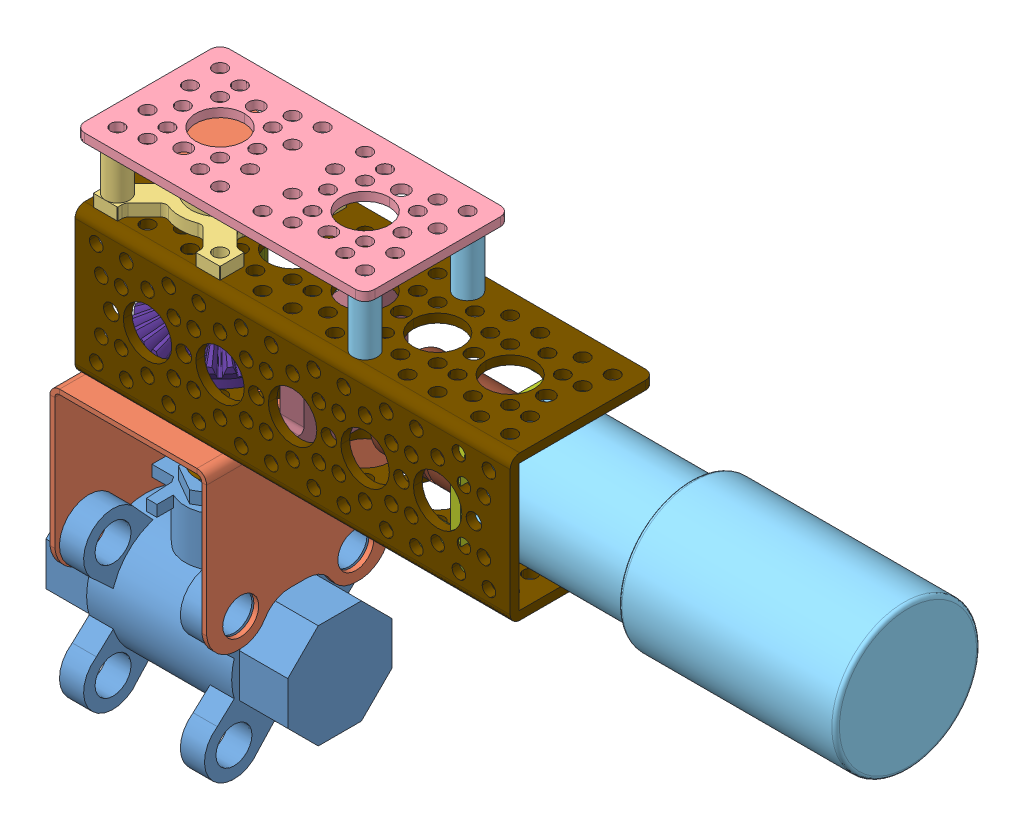
SolidWorks assembly MFV v3.1, configuration Default. Lengths in mm.
Overall size (226.04 151.59 90.41).
38 component instances, 23 part files, 48 mates.
Components (placement in the parent):
- Sharpe 39036-1: Sharpe 39036 [Default] at (-24.652 -21.0473 11.0376) size (63.5 64.02 45.72)
- Base v3-1: Base v3 [Default] at (-5.348 29.6257 11.0376) x (0 0 1) z (1 0 0) size (48.16 44.23 41.15)
- 535110 assembly - Pillow-1: 535110 assembly - Pillow [Default] at (22.7078 53.748 4.1263) x (0 0 1) z (-1 0 0) size (33.27 5.08 33.27)
  - 535110 assembly - Pillow.STEP-1: 535110 assembly - Pillow.STEP [Default] at origin size (33.27 5.08 33.27)
    - 535110.STEP-1: 535110.STEP [Default] at (6.6273 15.2478 28.3097) size (33.27 5.08 33.27)
    - 535020.STEP-1: 535020.STEP [Default] at (6.6273 17.9338 28.3097) size (12.7 4.76 12.7)
- Motor_12VDC_638263-1: Motor_12VDC_638263 [Default] at (73.1868 50.0105 10.7536) x (0 -0.998999 -0.044744) z (0 0.044744 -0.998999) size (38 101.9 38)
- Motor_12VDC_638263_shaft-1: Motor_12VDC_638263_shaft [Default] at (73.1868 50.0105 10.7536) x (0 -0.998999 -0.044744) z (0 0.044744 -0.998999) size (6 16.2 6)
- 555188 assembly.STEP-1: 555188 assembly.STEP [Default] at (77.9607 56.4898 13.3688) x (0 1 0) z (0 0 1) size (33.4 16.56 37.36)
  - 555188.STEP-1: 555188.STEP [Default] at (-6.4793 1.7739 -2.6152) size (33.4 14.22 37.36)
  - 555188 screw_92005A116.STEP-1: 555188 screw_92005A116.STEP [Default] at (-15.6717 7.7739 6.5772) x (1 0 0) z (0 -1 0) size (6 6 8.35)
  - 555188 screw_92005A116.STEP-2: 555188 screw_92005A116.STEP [Default] at (2.7131 7.7739 6.5772) x (0 0 -1) z (0 -1 0) size (6 6 8.35)
  - 555188 screw_92005A116.STEP-3: 555188 screw_92005A116.STEP [Default] at (2.7131 7.7739 -11.8076) x (-1 0 0) z (0 -1 0) size (6 6 8.35)
  - 555188 screw_92005A116.STEP-4: 555188 screw_92005A116.STEP [Default] at (-15.6717 7.7739 -11.8076) x (0 0 1) z (0 -1 0) size (6 6 8.35)
- 625182 assembly-2: 625182 assembly [Default] at (62.7148 0.441 66.0915) x (0.514196 0 0.857672) z (-0.857672 0 0.514196) size (12.69 19.05 12.7)
- D-shaft-2.25in-1: D-shaft-2.25in [Default] at (-5.602 20.6122 10.7536) x (0.746779 0 -0.665072) z (0.665072 0 0.746779) size (5.71 57.15 6.35)
- 625100 assembly.STEP-1: 625100 assembly.STEP [Default] at (78.1702 76.4539 35.3179) x (0 0.726073 0.687617) z (-1 0 0) size (50.01 22.2 75.17)
  - 625100.STEP-1: 625100.STEP [Default] at (-36.0907 -0.3474 4.9835) size (22.23 22.2 28.57)
  - 632112_90128A121.STEP-1: 632112_90128A121.STEP [Default] at (-1.3244 -7.8756 30.0025) x (0 0 -1) z (1 0 0) size (5.61 5.61 14.62)
  - 632112_90128A121.STEP-2: 632112_90128A121.STEP [Default] at (-1.3244 -7.8756 23.5255) x (0 0 -1) z (1 0 0) size (5.61 5.61 14.62)
  - 632112_90128A121.STEP-3: 632112_90128A121.STEP [Default] at (-1.3244 -7.8756 15.0165) x (0 0 -1) z (1 0 0) size (5.61 5.61 14.62)
  - 632112_90128A121.STEP-4: 632112_90128A121.STEP [Default] at (-1.3244 -7.8756 8.5395) x (0 0 -1) z (1 0 0) size (5.61 5.61 14.62)
- 535130 assembly.STEP-1: 535130 assembly.STEP [Default] at (9.528 42.3273 39.1453) x (0 1 0) z (0 0 -1) size (33.54 6.36 33.02)
  - 535130.STEP-1: 535130.STEP [Default] at (7.6184 14.2154 28.3917) size (33.54 6.36 33.02)
  - 535020.STEP-1: 535020.STEP [Default] at (7.6184 18.1715 28.3917) size (12.7 4.76 12.7)
- 615458 assembly.STEP-1: 615458 assembly.STEP [Default] at (-48.1481 74.9588 -4.9667) x (-1 0 0) z (0 -0.723056 0.690789) size (72.51 19.24 80.12)
  - 615458.STEP-1: 615458.STEP [Default] at (-61.4441 5.8673 28.8984) size (15.1 19.24 19.22)
  - 632110_90128A121.STEP-1: 632110_90128A121.STEP [Default] at (-66.148 1.368 -6.0266) x (-0.354662 -0.934995 0) z (0 0 -1) size (5.61 5.61 13.03)
- 545309.step-1: 545309.step [Default] at (-5.602 50.6898 10.7536) x (0.920966 0 -0.389644) z (0 -1 0) size (17.78 17.76 20.07)
- 615460.step-1: 615460.step [Default] at (-5.602 40.7317 10.7536) x (0 1 0) z (-0.857986 0 0.513673) size (8.04 33.75 33.87)
- 585444-1: 585444 [Default] at (-24.652 68.9957 29.8036) x (0 -1 0) z (1 0 0) size (38.1 38.1 114.3)
- D-shaft-2in-3: D-shaft-2in [Default] at (7.4008 50.0105 10.7536) x (0 -0.983443 -0.181218) z (0 -0.181218 0.983443) size (5.71 50.8 6.35)
- AS5047 eval board-1: AS5047 eval board [Default] at (-1.127 83.6007 10.8603) size (28 1.27 22)
- 0.5in standoff-2: 0.5in standoff [Default] at (-19.0724 72.1707 -2.7168) x (0.095865 0 0.995394) z (-0.995394 0 0.095865) size (6.35 12.7 6.35)
- 0.5in standoff-4: 0.5in standoff [Default] at (-19.0724 72.1707 24.224) x (0.320114 0 -0.947379) z (0.947379 0 0.320114) size (6.35 12.7 6.35)
- 585422.step-1: 585422.step [Default] at (13.448 84.8707 10.7536) size (76.2 2.29 38.1)
- .625in standoff-1: .625in standoff [Default] at (45.9684 84.8707 24.224) x (-0.852653 0 -0.522477) z (-0.522477 0 0.852653) size (6.35 15.88 6.35)
- .625in standoff-2: .625in standoff [Default] at (45.9684 68.9957 -2.7168) x (0.998481 0 -0.055099) z (0.055099 0 0.998481) size (6.35 15.88 6.35)
Mates (geometry in assembly coordinates):
- Concentric3: concentric: circle of Sharpe 39036-1; circle of Base v3-1
- Concentric4: concentric: cylinder of Sharpe 39036-1 through (13.448 -5.9343 26.1506) axis (-1 0 0) radius 4.7307; circle of Base v3-1
- Coincident4: coincident: plane of Sharpe 39036-1 through (-24.652 -21.0473 11.0376) normal (-1 0 0); plane of Base v3-1 through (-24.652 29.6257 11.0376) normal (1 0 0)
- Concentric8: concentric: circle of Motor_12VDC_638263-1; circle of Motor_12VDC_638263_shaft-1
- Coincident8: coincident: plane of Motor_12VDC_638263-1 through (73.1868 50.0105 10.7536) normal (-1 0 0); plane of Motor_12VDC_638263_shaft-1 through (73.1868 50.0105 10.7536) normal (1 0 0)
- Concentric10: concentric: cylinder of Motor_12VDC_638263-1 through (117.9868 50.0105 10.7536) axis (-1 0 0) radius 16; circle of 555188 assembly.STEP-1/555188.STEP-1
- Distance4: distance = 2.54 mm: plane of Motor_12VDC_638263-1 through (76.1868 50.0105 10.7536) normal (-1 0 0); plane of 555188 assembly.STEP-1/555188.STEP-1 through (73.6468 50.0105 10.7536) normal (-1 0 0)
- Concentric12: concentric: cylinder of Sharpe 39036-1 through (-5.602 20.1165 10.7536) axis (0 -1 0) radius 3.937; cylinder of 625182 assembly-2 through (-5.602 29.6415 10.7536) axis (0 1 0) radius 3.175
- Distance1: distance = 0.254 mm: plane of 625182 assembly-2 through (-5.602 10.5915 10.7536) normal (0 -1 0); plane of Sharpe 39036-1 through (-5.602 10.3375 10.7536) normal (0 1 0)
- Coincident16: coincident: circle of 625182 assembly-2; plane of D-shaft-2.25in-1 through (-5.602 20.6122 10.7536) normal (0 -1 0)
- Concentric13: concentric: cylinder of 625182 assembly-2 through (-5.602 29.6415 10.7536) axis (0 1 0) radius 3.175; cylinder of D-shaft-2.25in-1 through (-5.602 77.7622 10.7536) axis (0 -1 0) radius 3.175
- Concentric20: concentric: cylinder of Motor_12VDC_638263_shaft-1 through (56.9868 50.0105 10.7536) axis (1 0 0) radius 3; cylinder of 625100 assembly.STEP-1/625100.STEP-1 through (58.8993 50.0105 10.7536) axis (-1 0 0) radius 3
- Coincident25: coincident: plane of Motor_12VDC_638263-1 through (73.1868 50.0105 10.7536) normal (-1 0 0); plane of 625100 assembly.STEP-1/625100.STEP-1 through (73.1868 50.0105 10.7536) normal (1 0 0)
- Concentric21: concentric: cylinder of D-shaft-2.25in-1 through (-5.602 77.7622 10.7536) axis (0 -1 0) radius 3.175; cylinder of 545309.step-1 through (-5.602 44.3398 10.7536) axis (0 1 0) radius 3.175
- Coincident26: coincident: cylinder of D-shaft-2.25in-1 through (-5.602 77.7622 10.7536) axis (0 -1 0) radius 3.175; circle of 615460.step-1
- Coincident28: coincident: plane of 545309.step-1 through (-5.602 44.3398 10.7536) normal (0 -1 0); plane of 615460.step-1 through (-5.602 44.3398 10.7536) normal (0 1 0)
- Concentric22: concentric: cylinder of 625100 assembly.STEP-1/625100.STEP-1 through (58.8993 50.0105 10.7536) axis (-1 0 0) radius 3; cylinder of 615458 assembly.STEP-1/615458.STEP-1 through (6.4231 50.0105 10.7536) axis (1 0 0) radius 3
- Coincident31: coincident: plane of Base v3-1 through (-5.348 30.8957 11.0376) normal (0 1 0); plane of 585444-1 through (89.648 30.8957 -8.2964) normal (0 -1 0)
- Concentric25: concentric: cylinder of Sharpe 39036-1 through (-5.602 10.3375 10.7536) axis (0 -1 0) radius 4.6736; cylinder of 585444-1 through (-5.602 30.8957 10.7536) axis (0 -1 0) radius 6.3627
- Parallel2: parallel: plane of Base v3-1 through (-5.348 30.8957 11.0376) normal (0 1 0); line of 585444-1 through (87.108 33.1817 -8.2964) axis (-1 0 0)
- Coincident34: coincident: plane of 535130 assembly.STEP-1/535130.STEP-1 through (30.0934 66.7097 -5.7564) normal (0 1 0); plane of 585444-1 through (89.648 66.7097 -8.2964) normal (0 -1 0)
- Concentric28: concentric: cylinder of 535130 assembly.STEP-1/535130.STEP-1 through (26.9184 66.7097 -2.7168) axis (0 1 0) radius 1.3526; cylinder of 585444-1 through (26.9184 30.8957 -2.7168) axis (0 -1 0) radius 1.778
- Concentric29: concentric: cylinder of 535130 assembly.STEP-1/535130.STEP-1 through (26.9184 66.7097 24.224) axis (0 1 0) radius 1.3526; cylinder of 585444-1 through (26.9184 30.8957 24.224) axis (0 -1 0) radius 1.778
- Parallel3: parallel: line of Base v3-1 through (-23.382 30.8957 -13.0416) axis (1 0 0); line of 585444-1 through (87.108 33.1817 -8.2964) axis (-1 0 0)
- Concentric31: concentric: circle of 555188 assembly.STEP-1/555188.STEP-1; cylinder of 585444-1 through (65.0184 30.8957 -2.7168) axis (0 -1 0) radius 1.778
- Concentric32: concentric: cylinder of 625100 assembly.STEP-1/625100.STEP-1 through (58.8993 50.0105 10.7536) axis (-1 0 0) radius 3; cylinder of D-shaft-2in-3 through (58.2008 50.0105 10.7536) axis (-1 0 0) radius 3.175
- Coincident36: coincident: plane of 625100 assembly.STEP-1/625100.STEP-1 through (58.2008 34.3204 11.1603) normal (1 0 0); plane of D-shaft-2in-3 through (58.2008 50.0105 10.7536) normal (1 0 0)
- Concentric35: concentric: cylinder of 0.5in standoff-4 through (-19.0724 84.8707 24.224) axis (0 -1 0) radius 3.175; cylinder of 585422.step-1 through (-19.0724 87.1567 24.224) axis (0 1 0) radius 1.778
- Concentric36: concentric: cylinder of 0.5in standoff-2 through (-19.0724 84.8707 -2.7168) axis (0 -1 0) radius 3.175; cylinder of 585422.step-1 through (-19.0724 87.1567 -2.7168) axis (0 1 0) radius 1.778
- Coincident42: coincident: plane of 0.5in standoff-2 through (-19.0724 84.8707 -2.7168) normal (0 1 0); plane of 585422.step-1 through (13.448 84.8707 10.7536) normal (0 -1 0)
- Coincident43: coincident: plane of 585422.step-1 through (13.448 84.8707 10.7536) normal (0 -1 0); plane of .625in standoff-2 through (45.9684 84.8707 -2.7168) normal (0 1 0)
- Concentric38: concentric: circle of 585422.step-1; cylinder of .625in standoff-2 through (45.9684 84.8707 -2.7168) axis (0 -1 0) radius 3.175
- Concentric39: concentric: cylinder of .625in standoff-1 through (45.9684 68.9957 24.224) axis (0 1 0) radius 3.175; cylinder of 585422.step-1 through (45.9684 87.1567 24.224) axis (0 1 0) radius 1.778
- Coincident44: coincident: plane of 585422.step-1 through (13.448 84.8707 10.7536) normal (0 -1 0); plane of .625in standoff-1 through (45.9684 84.8707 24.224) normal (0 1 0)
- Coincident45: coincident: plane of AS5047 eval board-1 through (-1.127 84.8707 10.8603) normal (0 1 0); plane of 585422.step-1 through (13.448 84.8707 10.7536) normal (0 -1 0)
- Parallel4: parallel: line of AS5047 eval board-1 through (-15.127 84.8707 21.8603) axis (1 0 0); plane of 585422.step-1 through (-24.652 87.1567 29.8036) normal (0 0 1)
- Distance6: distance = 8.255 mm: line of AS5047 eval board-1 through (12.873 83.6007 -0.1397) axis (-1 0 0); line of 585422.step-1 through (49.008 84.8707 -8.2964) axis (-1 0 0)
- Coincident47: coincident: plane of D-shaft-2in-3 through (7.4008 50.0105 10.7536) normal (-1 0 0); plane of 615458 assembly.STEP-1/615458.STEP-1 through (7.4008 50.0105 10.7536) normal (-1 0 0)
- Coincident48: coincident: plane of 555188 assembly.STEP-1/555188.STEP-1 through (73.6468 66.7097 27.2128) normal (0 1 0); plane of 585444-1 through (89.648 66.7097 -8.2964) normal (0 -1 0)
- Concentric40: concentric: circle of 555188 assembly.STEP-1/555188.STEP-1; cylinder of 585444-1 through (65.0184 30.8957 24.224) axis (0 -1 0) radius 1.778
- Concentric41: concentric: cylinder of 585444-1 through (-19.0724 30.8957 -2.7168) axis (0 -1 0) radius 1.778; cylinder of 0.5in standoff-2 through (-19.0724 84.8707 -2.7168) axis (0 -1 0) radius 3.175
- Coincident49: coincident: plane of 0.5in standoff-4 through (-19.0724 84.8707 24.224) normal (0 1 0); plane of 585422.step-1 through (13.448 84.8707 10.7536) normal (0 -1 0)
- Concentric42: concentric: cylinder of 585444-1 through (-19.0724 30.8957 24.224) axis (0 -1 0) radius 1.778; cylinder of 0.5in standoff-4 through (-19.0724 84.8707 24.224) axis (0 -1 0) radius 3.175
- Distance7: distance = 3.175 mm: plane of 585444-1 through (89.648 68.9957 29.8036) normal (0 1 0); plane of 0.5in standoff-4 through (-19.0724 72.1707 24.224) normal (0 -1 0)
- Distance8: distance = 9.525 mm: plane of 585422.step-1 through (-24.652 87.1567 29.8036) normal (-1 0 0); plane of AS5047 eval board-1 through (-15.127 84.8707 -0.1397) normal (-1 0 0)
- Concentric44: concentric: circle of 535110 assembly - Pillow-1/535110 assembly - Pillow.STEP-1/535110.STEP-1; cylinder of D-shaft-2.25in-1 through (-5.602 77.7622 10.7536) axis (0 -1 0) radius 3.175
- Coincident52: coincident: plane of 535110 assembly - Pillow-1/535110 assembly - Pillow.STEP-1/535110.STEP-1 through (-5.602 68.9957 10.7536) normal (0 -1 0); plane of 585444-1 through (89.648 68.9957 29.8036) normal (0 1 0)
- Concentric45: concentric: cylinder of 535110 assembly - Pillow-1/535110 assembly - Pillow.STEP-1/535110.STEP-1 through (7.8684 72.1707 -2.7168) axis (0 1 0) radius 1.778; cylinder of 585444-1 through (7.8684 30.8957 -2.7168) axis (0 -1 0) radius 1.778
